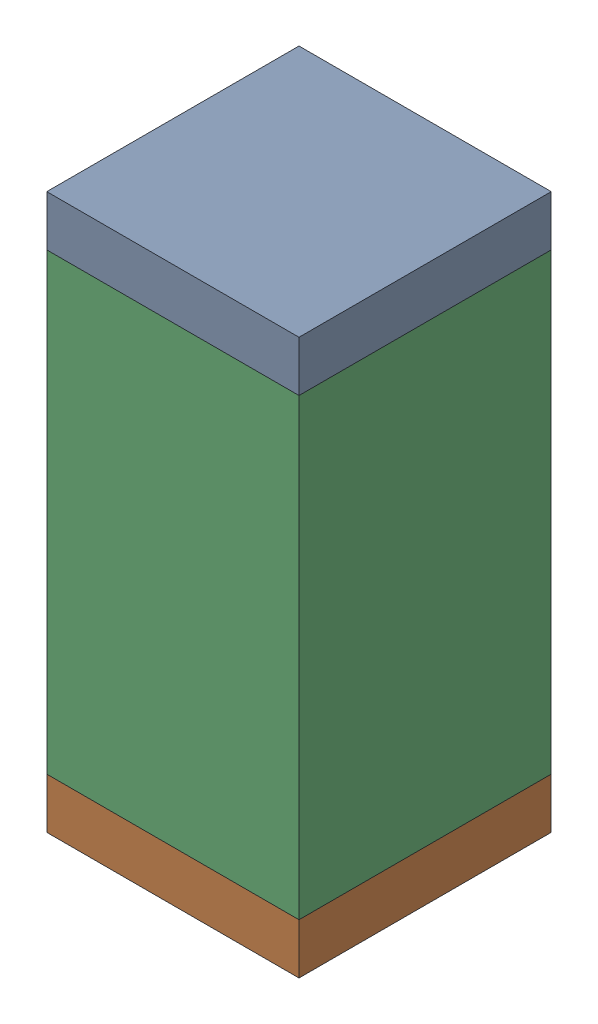
SolidWorks assembly C17, configuration Default. Lengths in mm.
Overall size (0.5 1.1 0.5).
6 component instances, 2 part files, 0 mates.
Components (placement in the parent):
- 810157360-1: 810157360 [Default] at (134.5 15.8 0) size (0.5 0.1 0.5)
  - Extruded_9-1: Extruded_9 [Default] at origin size (0.5 0.1 0.5)
- 810157360-2: 810157360 [Default] at (134.5 14.8 0) size (0.5 0.1 0.5)
  - Extruded_9-1: Extruded_9 [Default] at origin size (0.5 0.1 0.5)
- 791586336-1: 791586336 [Default] at (134.5 15.3 0) size (0.5 0.9 0.5)
  - Extruded_8-1: Extruded_8 [Default] at origin size (0.5 0.9 0.5)
